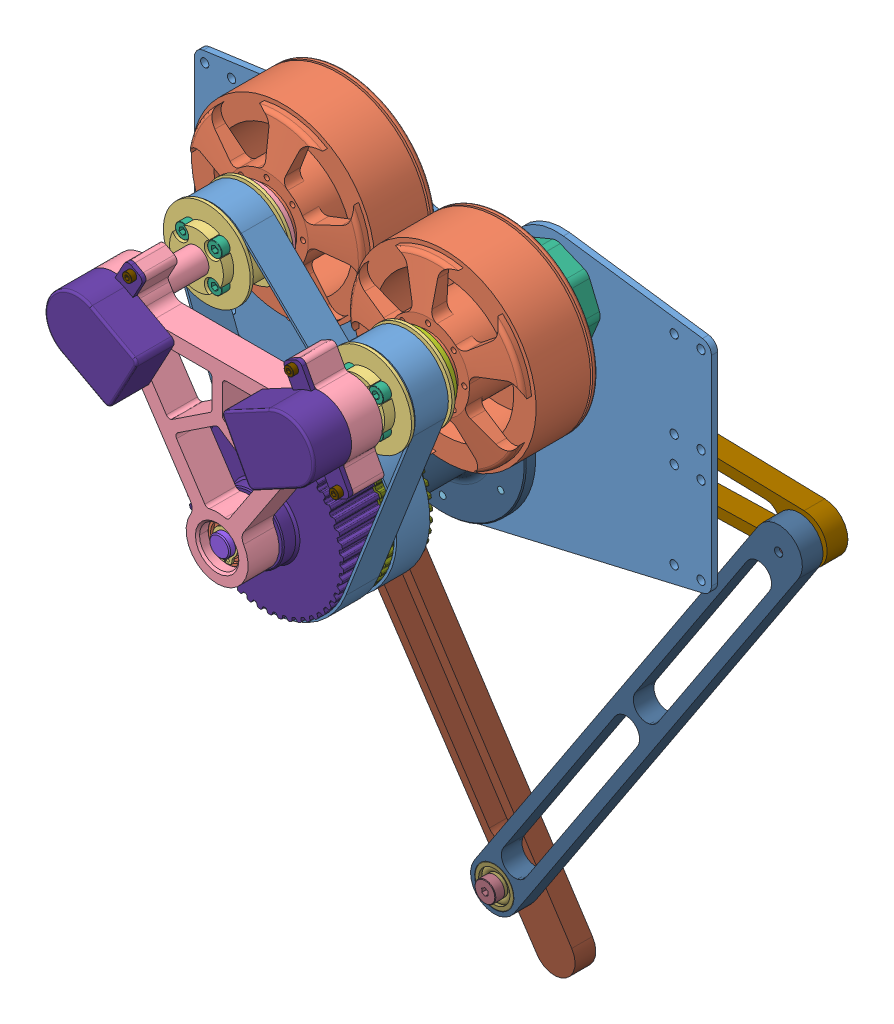
SolidWorks assembly Assembly, configuration Default. Lengths in mm.
Overall size (312.75 390.32 178.8).
163 component instances, 37 part files, 104 mates.
Components (placement in the parent):
- Mounting Plate-1: Mounting Plate [Default] at (803.8236 318.9692 0) size (250 143.05 3)
- Long Motor Assembly-1: Long Motor Assembly [Default] at (703.2032 181.8732 -91.3778) size (125.3 125.3 113)
  - T-Motor U10 KV80-1: T-Motor U10 KV80 [Default] at (50.6204 137.0959 94.3778) x (0.707107 -0.707107 0) z (0 0 1) size (88.6 88.6 43)
  - Timing Belt Pulley-1: Timing Belt Pulley [Default] at (50.6204 137.0959 142.3778) x (-0.707107 0.707107 0) z (0 0 -1) size (42 42 26)
  - Motor Shaft Long-1: Motor Shaft Long [Default] at (50.6204 137.0959 137.3778) x (0 -1 0) z (0 0 1) size (34 34 90)
  - ISO 10642 - M4 x 12 - 12C-9: ISO 10642 - M4 x 12 - 12C [ISO 10642 - M4 x 12 - 12C] at (50.6204 148.5959 142.3578) x (0 0 -1) z (0.997572 0.069644 0) size (12 7.53 7.53)
  - ISO 10642 - M4 x 12 - 12C-10: ISO 10642 - M4 x 12 - 12C [ISO 10642 - M4 x 12 - 12C] at (62.1204 137.0959 142.3578) x (0 0 -1) z (1 0 0) size (12 7.53 7.53)
  - ISO 10642 - M4 x 12 - 12C-11: ISO 10642 - M4 x 12 - 12C [ISO 10642 - M4 x 12 - 12C] at (39.1204 137.0959 142.3578) x (0 0 -1) z (1 0 0) size (12 7.53 7.53)
  - ISO 10642 - M4 x 12 - 12C-12: ISO 10642 - M4 x 12 - 12C [ISO 10642 - M4 x 12 - 12C] at (50.6204 125.5959 142.3578) x (0 0 -1) z (1 0 0) size (12 7.53 7.53)
  - ISO 4762 M4 x 25 - 25C-2: ISO 4762 M4 x 25 - 25C [PreviewCfg] at (58.3986 144.8741 167.3778) x (0 0 -1) z (1 0 0) size (29 7 7)
  - ISO 4762 M4 x 25 - 25C-4: ISO 4762 M4 x 25 - 25C [ISO 4762 M4 x 25 - 25C] at (42.8422 144.8741 167.3778) x (0 0 -1) z (0.999681 -0.025261 0) size (29 7 7)
  - ISO 4762 M4 x 25 - 25C-6: ISO 4762 M4 x 25 - 25C [ISO 4762 M4 x 25 - 25C] at (42.8422 129.3178 167.3778) x (0 0 -1) z (1 0 0) size (29 7 7)
  - ISO 4762 M4 x 25 - 25C-8: ISO 4762 M4 x 25 - 25C [ISO 4762 M4 x 25 - 25C] at (58.3986 129.3178 167.3778) x (0 0 -1) z (1 0 0) size (29 7 7)
- Short Motor Assembly-1: Short Motor Assembly [Default] at (703.2032 181.8732 -91.3778) size (125.3 125.3 91)
  - T-Motor U10 KV80-1: T-Motor U10 KV80 [Default] at (150.6204 137.0959 116.3778) x (0.707107 0.707107 0) z (0 0 1) size (88.6 88.6 43)
  - Timing Belt Pulley-1: Timing Belt Pulley [Default] at (150.6204 137.0959 164.3778) x (0.707107 0.707107 0) z (0 0 -1) size (42 42 26)
  - Motor Shaft Short-1: Motor Shaft Short [Default] at (150.6204 137.0959 159.3778) x (0 1 0) z (0 0 1) size (34 34 68)
  - ISO 10642 - M4 x 12 - 12C-9: ISO 10642 - M4 x 12 - 12C [ISO 10642 - M4 x 12 - 12C] at (139.1204 137.0959 164.3578) x (0 0 -1) z (1 -0.000264 0) size (12 7.53 7.53)
  - ISO 10642 - M4 x 12 - 12C-10: ISO 10642 - M4 x 12 - 12C [ISO 10642 - M4 x 12 - 12C] at (150.6204 148.5959 164.3578) x (0 0 -1) z (1 0 0) size (12 7.53 7.53)
  - ISO 10642 - M4 x 12 - 12C-11: ISO 10642 - M4 x 12 - 12C [ISO 10642 - M4 x 12 - 12C] at (162.1204 137.0959 164.3578) x (0 0 -1) z (1 0 0) size (12 7.53 7.53)
  - ISO 4762 M4 x 25 - 25C-2: ISO 4762 M4 x 25 - 25C [PreviewCfg] at (142.8422 144.8741 189.3778) x (0 0 -1) z (1 0 0) size (29 7 7)
  - ISO 4762 M4 x 25 - 25C-4: ISO 4762 M4 x 25 - 25C [ISO 4762 M4 x 25 - 25C] at (158.3986 129.3178 189.3778) x (0 0 -1) z (1 0 0) size (29 7 7)
  - ISO 4762 M4 x 25 - 25C-6: ISO 4762 M4 x 25 - 25C [ISO 4762 M4 x 25 - 25C] at (158.3986 144.8741 189.3778) x (0 0 -1) z (1 0 0) size (29 7 7)
  - ISO 10642 - M4 x 12 - 12C-12: ISO 10642 - M4 x 12 - 12C [ISO 10642 - M4 x 12 - 12C] at (150.6204 125.5959 164.3578) x (0 0 -1) z (1 0 0) size (12 7.53 7.53)
  - ISO 4762 M4 x 25 - 25C-8: ISO 4762 M4 x 25 - 25C [ISO 4762 M4 x 25 - 25C] at (142.8422 129.3178 189.3778) x (0 0 -1) z (1 0 0) size (29 7 7)
- Coaxial Shaft Assembly-1: Coaxial Shaft Assembly [Default] at (709.5255 181.8732 -91.3778) size (109.28 109.28 155)
  - Inner Shaft-1: Inner Shaft [Default] at (94.2981 61.5422 207.3778) x (0 0 -1) z (1 0 0) size (155 12 12)
  - Outer Shaft-1: Outer Shaft [Default] at (94.2981 61.5422 163.3778) x (0 0 -1) z (-1 0 0) size (100.5 20 20)
  - Flange-1: Flange [Default] at (94.2981 61.5422 94.3778) x (-0.866025 0.5 0) z (0 0 1) size (80 80 40)
  - SKF - 61804 - 18,SI,NC,18_68-5: SKF - 61804 - 18,SI,NC,18_68 [SKF - 61804 - 18,SI,NC,18_68] at (94.2981 61.5422 97.8778) x (0 0 1) z (-0.071685 -0.997427 0) size (7 32 32)
  - SKF - 61804 - 18,SI,NC,18_68-6: SKF - 61804 - 18,SI,NC,18_68 [SKF - 61804 - 18,SI,NC,18_68] at (94.2981 61.5422 130.8778) x (0 0 1) z (-1 0 0) size (7 32 32)
  - Circlip DIN 471 - 20 x 1.2-3: Circlip DIN 471 - 20 x 1.2 [Circlip DIN 471 - 20 x 1.2] at (94.2981 61.5422 93.0778) x (-1 0 0) z (0 0 -1) size (22.81 25.6 1.2)
  - HK_1210-1: HK_1210 [Default] at (94.2981 61.5422 163.3778) x (0 0 -1) z (1 0 0) size (10 16 16)
    - _HK_1210_PART1_2-1: _HK_1210_PART1_2 [Default] at origin size (10 16 16)
    - _HK_1210_PART2_4-1: _HK_1210_PART2_4 [Default] at origin size (6.3 1.5 1.5)
    - _HK_1210_PART2_4-2: _HK_1210_PART2_4 [Default] x (1 0 0) z (0 0.34202 0.939693) size (6.3 1.5 1.5)
    - _HK_1210_PART2_4-3: _HK_1210_PART2_4 [Default] x (1 0 0) z (0 0.642788 0.766044) size (6.3 1.5 1.5)
    - _HK_1210_PART2_4-4: _HK_1210_PART2_4 [Default] x (1 0 0) z (0 0.866025 0.5) size (6.3 1.5 1.5)
    - _HK_1210_PART2_4-5: _HK_1210_PART2_4 [Default] x (1 0 0) z (0 0.984808 0.173648) size (6.3 1.5 1.5)
    - _HK_1210_PART2_4-6: _HK_1210_PART2_4 [Default] x (1 0 0) z (0 0.984808 -0.173648) size (6.3 1.5 1.5)
    - _HK_1210_PART2_4-7: _HK_1210_PART2_4 [Default] x (1 0 0) z (0 0.866025 -0.5) size (6.3 1.5 1.5)
    - _HK_1210_PART2_4-8: _HK_1210_PART2_4 [Default] x (1 0 0) z (0 0.642788 -0.766044) size (6.3 1.5 1.5)
    - _HK_1210_PART2_4-9: _HK_1210_PART2_4 [Default] x (1 0 0) z (0 0.34202 -0.939693) size (6.3 1.5 1.5)
    - _HK_1210_PART2_4-10: _HK_1210_PART2_4 [Default] x (1 0 0) z (0 0 -1) size (6.3 1.5 1.5)
    - _HK_1210_PART2_4-11: _HK_1210_PART2_4 [Default] x (1 0 0) z (0 -0.34202 -0.939693) size (6.3 1.5 1.5)
    - _HK_1210_PART2_4-12: _HK_1210_PART2_4 [Default] x (1 0 0) z (0 -0.642788 -0.766044) size (6.3 1.5 1.5)
    - _HK_1210_PART2_4-13: _HK_1210_PART2_4 [Default] x (1 0 0) z (0 -0.866025 -0.5) size (6.3 1.5 1.5)
    - _HK_1210_PART2_4-14: _HK_1210_PART2_4 [Default] x (1 0 0) z (0 -0.984808 -0.173648) size (6.3 1.5 1.5)
    - _HK_1210_PART2_4-15: _HK_1210_PART2_4 [Default] x (1 0 0) z (0 -0.984808 0.173648) size (6.3 1.5 1.5)
    - _HK_1210_PART2_4-16: _HK_1210_PART2_4 [Default] x (1 0 0) z (0 -0.866025 0.5) size (6.3 1.5 1.5)
    - _HK_1210_PART2_4-17: _HK_1210_PART2_4 [Default] x (1 0 0) z (0 -0.642788 0.766044) size (6.3 1.5 1.5)
    - _HK_1210_PART2_4-18: _HK_1210_PART2_4 [Default] x (1 0 0) z (0 -0.34202 0.939693) size (6.3 1.5 1.5)
    - _HK_1210_PART3_23-1: _HK_1210_PART3_23 [Default] at origin size (6.3 1.5 1.5)
    - _HK_1210_PART3_23-2: _HK_1210_PART3_23 [Default] x (1 0 0) z (0 0.34202 0.939693) size (6.3 1.5 1.5)
    - _HK_1210_PART3_23-3: _HK_1210_PART3_23 [Default] x (1 0 0) z (0 0.642788 0.766044) size (6.3 1.5 1.5)
    - _HK_1210_PART3_23-4: _HK_1210_PART3_23 [Default] x (1 0 0) z (0 0.866025 0.5) size (6.3 1.5 1.5)
    - _HK_1210_PART3_23-5: _HK_1210_PART3_23 [Default] x (1 0 0) z (0 0.984808 0.173648) size (6.3 1.5 1.5)
    - _HK_1210_PART3_23-6: _HK_1210_PART3_23 [Default] x (1 0 0) z (0 0.984808 -0.173648) size (6.3 1.5 1.5)
    - _HK_1210_PART3_23-7: _HK_1210_PART3_23 [Default] x (1 0 0) z (0 0.866025 -0.5) size (6.3 1.5 1.5)
    - _HK_1210_PART3_23-8: _HK_1210_PART3_23 [Default] x (1 0 0) z (0 0.642788 -0.766044) size (6.3 1.5 1.5)
    - _HK_1210_PART3_23-9: _HK_1210_PART3_23 [Default] x (1 0 0) z (0 0.34202 -0.939693) size (6.3 1.5 1.5)
    - _HK_1210_PART3_23-10: _HK_1210_PART3_23 [Default] x (1 0 0) z (0 0 -1) size (6.3 1.5 1.5)
    - _HK_1210_PART3_23-11: _HK_1210_PART3_23 [Default] x (1 0 0) z (0 -0.34202 -0.939693) size (6.3 1.5 1.5)
    - _HK_1210_PART3_23-12: _HK_1210_PART3_23 [Default] x (1 0 0) z (0 -0.642788 -0.766044) size (6.3 1.5 1.5)
    - _HK_1210_PART3_23-13: _HK_1210_PART3_23 [Default] x (1 0 0) z (0 -0.866025 -0.5) size (6.3 1.5 1.5)
    - _HK_1210_PART3_23-14: _HK_1210_PART3_23 [Default] x (1 0 0) z (0 -0.984808 -0.173648) size (6.3 1.5 1.5)
    - _HK_1210_PART3_23-15: _HK_1210_PART3_23 [Default] x (1 0 0) z (0 -0.984808 0.173648) size (6.3 1.5 1.5)
    - _HK_1210_PART3_23-16: _HK_1210_PART3_23 [Default] x (1 0 0) z (0 -0.866025 0.5) size (6.3 1.5 1.5)
    - _HK_1210_PART3_23-17: _HK_1210_PART3_23 [Default] x (1 0 0) z (0 -0.642788 0.766044) size (6.3 1.5 1.5)
    - _HK_1210_PART3_23-18: _HK_1210_PART3_23 [Default] x (1 0 0) z (0 -0.34202 0.939693) size (6.3 1.5 1.5)
  - HK_1210-2: HK_1210 [Default] at (94.2981 61.5422 72.8778) x (0 0 -1) z (1 0 0) size (10 16 16)
    - _HK_1210_PART1_2-1: _HK_1210_PART1_2 [Default] at origin size (10 16 16)
    - _HK_1210_PART2_4-1: _HK_1210_PART2_4 [Default] at origin size (6.3 1.5 1.5)
    - _HK_1210_PART2_4-2: _HK_1210_PART2_4 [Default] x (1 0 0) z (0 0.34202 0.939693) size (6.3 1.5 1.5)
    - _HK_1210_PART2_4-3: _HK_1210_PART2_4 [Default] x (1 0 0) z (0 0.642788 0.766044) size (6.3 1.5 1.5)
    - _HK_1210_PART2_4-4: _HK_1210_PART2_4 [Default] x (1 0 0) z (0 0.866025 0.5) size (6.3 1.5 1.5)
    - _HK_1210_PART2_4-5: _HK_1210_PART2_4 [Default] x (1 0 0) z (0 0.984808 0.173648) size (6.3 1.5 1.5)
    - _HK_1210_PART2_4-6: _HK_1210_PART2_4 [Default] x (1 0 0) z (0 0.984808 -0.173648) size (6.3 1.5 1.5)
    - _HK_1210_PART2_4-7: _HK_1210_PART2_4 [Default] x (1 0 0) z (0 0.866025 -0.5) size (6.3 1.5 1.5)
    - _HK_1210_PART2_4-8: _HK_1210_PART2_4 [Default] x (1 0 0) z (0 0.642788 -0.766044) size (6.3 1.5 1.5)
    - _HK_1210_PART2_4-9: _HK_1210_PART2_4 [Default] x (1 0 0) z (0 0.34202 -0.939693) size (6.3 1.5 1.5)
    - _HK_1210_PART2_4-10: _HK_1210_PART2_4 [Default] x (1 0 0) z (0 0 -1) size (6.3 1.5 1.5)
    - _HK_1210_PART2_4-11: _HK_1210_PART2_4 [Default] x (1 0 0) z (0 -0.34202 -0.939693) size (6.3 1.5 1.5)
    - _HK_1210_PART2_4-12: _HK_1210_PART2_4 [Default] x (1 0 0) z (0 -0.642788 -0.766044) size (6.3 1.5 1.5)
    - _HK_1210_PART2_4-13: _HK_1210_PART2_4 [Default] x (1 0 0) z (0 -0.866025 -0.5) size (6.3 1.5 1.5)
    - _HK_1210_PART2_4-14: _HK_1210_PART2_4 [Default] x (1 0 0) z (0 -0.984808 -0.173648) size (6.3 1.5 1.5)
    - _HK_1210_PART2_4-15: _HK_1210_PART2_4 [Default] x (1 0 0) z (0 -0.984808 0.173648) size (6.3 1.5 1.5)
    - _HK_1210_PART2_4-16: _HK_1210_PART2_4 [Default] x (1 0 0) z (0 -0.866025 0.5) size (6.3 1.5 1.5)
    - _HK_1210_PART2_4-17: _HK_1210_PART2_4 [Default] x (1 0 0) z (0 -0.642788 0.766044) size (6.3 1.5 1.5)
    - _HK_1210_PART2_4-18: _HK_1210_PART2_4 [Default] x (1 0 0) z (0 -0.34202 0.939693) size (6.3 1.5 1.5)
    - _HK_1210_PART3_23-1: _HK_1210_PART3_23 [Default] at origin size (6.3 1.5 1.5)
    - _HK_1210_PART3_23-2: _HK_1210_PART3_23 [Default] x (1 0 0) z (0 0.34202 0.939693) size (6.3 1.5 1.5)
    - _HK_1210_PART3_23-3: _HK_1210_PART3_23 [Default] x (1 0 0) z (0 0.642788 0.766044) size (6.3 1.5 1.5)
    - _HK_1210_PART3_23-4: _HK_1210_PART3_23 [Default] x (1 0 0) z (0 0.866025 0.5) size (6.3 1.5 1.5)
    - _HK_1210_PART3_23-5: _HK_1210_PART3_23 [Default] x (1 0 0) z (0 0.984808 0.173648) size (6.3 1.5 1.5)
    - _HK_1210_PART3_23-6: _HK_1210_PART3_23 [Default] x (1 0 0) z (0 0.984808 -0.173648) size (6.3 1.5 1.5)
    - _HK_1210_PART3_23-7: _HK_1210_PART3_23 [Default] x (1 0 0) z (0 0.866025 -0.5) size (6.3 1.5 1.5)
    - _HK_1210_PART3_23-8: _HK_1210_PART3_23 [Default] x (1 0 0) z (0 0.642788 -0.766044) size (6.3 1.5 1.5)
    - _HK_1210_PART3_23-9: _HK_1210_PART3_23 [Default] x (1 0 0) z (0 0.34202 -0.939693) size (6.3 1.5 1.5)
    - _HK_1210_PART3_23-10: _HK_1210_PART3_23 [Default] x (1 0 0) z (0 0 -1) size (6.3 1.5 1.5)
    - _HK_1210_PART3_23-11: _HK_1210_PART3_23 [Default] x (1 0 0) z (0 -0.34202 -0.939693) size (6.3 1.5 1.5)
    - _HK_1210_PART3_23-12: _HK_1210_PART3_23 [Default] x (1 0 0) z (0 -0.642788 -0.766044) size (6.3 1.5 1.5)
    - _HK_1210_PART3_23-13: _HK_1210_PART3_23 [Default] x (1 0 0) z (0 -0.866025 -0.5) size (6.3 1.5 1.5)
    - _HK_1210_PART3_23-14: _HK_1210_PART3_23 [Default] x (1 0 0) z (0 -0.984808 -0.173648) size (6.3 1.5 1.5)
    - _HK_1210_PART3_23-15: _HK_1210_PART3_23 [Default] x (1 0 0) z (0 -0.984808 0.173648) size (6.3 1.5 1.5)
    - _HK_1210_PART3_23-16: _HK_1210_PART3_23 [Default] x (1 0 0) z (0 -0.866025 0.5) size (6.3 1.5 1.5)
    - _HK_1210_PART3_23-17: _HK_1210_PART3_23 [Default] x (1 0 0) z (0 -0.642788 0.766044) size (6.3 1.5 1.5)
    - _HK_1210_PART3_23-18: _HK_1210_PART3_23 [Default] x (1 0 0) z (0 -0.34202 0.939693) size (6.3 1.5 1.5)
  - Outer Timing Belt Gear-1: Outer Timing Belt Gear [Default] at (94.2981 61.5422 163.3778) x (1 0 0) z (0 0 -1) size (76.29 76.29 29)
  - Inner Timing Belt Gear-1: Inner Timing Belt Gear [Default] at (94.2981 61.5422 164.3778) size (76.29 76.29 28)
  - ISO 8734 - 4 x 32 - A - St-3: ISO 8734 - 4 x 32 - A - St [ISO 8734 - 4 x 32 - A - St] at (94.2981 45.5422 188.8778) x (0 1 0) z (0.480016 0 0.87726) size (32 4 4)
  - ISO 4762 M3 x 12 - 12C-3: ISO 4762 M3 x 12 - 12C [ISO 4762 M3 x 12 - 12C] at (94.2981 39.5422 138.8778) x (0 1 0) z (0.922632 0 -0.385681) size (15 5.5 5.5)
  - ISO 4762 M3 x 12 - 12C-4: ISO 4762 M3 x 12 - 12C [ISO 4762 M3 x 12 - 12C] at (94.2981 83.5422 138.8778) x (0 -1 0) z (0.974179 0 0.225776) size (15 5.5 5.5)
- SKF - 61800 - 14,SI,NC,14_68-5: SKF - 61800 - 14,SI,NC,14_68 [SKF - 61800 - 14,SI,NC,14_68] at (803.8236 243.4155 109.5) x (0 0 1) z (-0.331189 0.943564 0) size (5 19 19)
- Circlip DIN 471 - 10 x 1-8: Circlip DIN 471 - 10 x 1 [Circlip DIN 471 - 10 x 1] at (803.8236 243.4155 113.1) size (12.16 14.7 1)
- Support Brace-1: Support Brace [Default] at (803.8236 318.9692 109.5) x (-1 0 0) z (0 0 -1) size (131.26 114.86 15)
- SKF - 61800 - 14,SI,NC,14_68-6: SKF - 61800 - 14,SI,NC,14_68 [SKF - 61800 - 14,SI,NC,14_68] at (753.8236 318.9692 109.5) x (0 0 -1) z (-0.924864 0.380297 0) size (5 19 19)
- SKF - 61800 - 14,SI,NC,14_68-7: SKF - 61800 - 14,SI,NC,14_68 [SKF - 61800 - 14,SI,NC,14_68] at (853.8236 318.9692 109.5) x (0 0 -1) z (-0.072342 0.99738 0) size (5 19 19)
- Circlip DIN 471 - 10 x 1-9: Circlip DIN 471 - 10 x 1 [Circlip DIN 471 - 10 x 1] at (753.8236 318.9692 113.1) x (0.999962 0.008683 0) z (0 0 1) size (12.16 14.7 1)
- Circlip DIN 471 - 10 x 1-10: Circlip DIN 471 - 10 x 1 [Circlip DIN 471 - 10 x 1] at (853.8236 318.9692 113.1) x (0.996379 0.085026 0) z (0 0 1) size (12.16 14.7 1)
- ISO 4762 M4 x 8 - 8C-38: ISO 4762 M4 x 8 - 8C [ISO 4762 M4 x 8 - 8C] at (753.8236 334.9692 -4) x (0 0 1) z (-1 0 0) size (12 7 7)
- ISO 4762 M4 x 8 - 8C-39: ISO 4762 M4 x 8 - 8C [ISO 4762 M4 x 8 - 8C] at (769.8236 318.9692 -4) x (0 0 1) z (-1 0 0) size (12 7 7)
- ISO 4762 M4 x 8 - 8C-40: ISO 4762 M4 x 8 - 8C [ISO 4762 M4 x 8 - 8C] at (753.8236 302.9692 -4) x (0 0 1) z (-1 0 0) size (12 7 7)
- ISO 4762 M4 x 8 - 8C-41: ISO 4762 M4 x 8 - 8C [ISO 4762 M4 x 8 - 8C] at (737.8236 318.9692 -4) x (0 0 1) z (-1 0 0) size (12 7 7)
- Motor Mounting-1: Motor Mounting [Default] at (853.8236 318.9692 3) size (42.47 42.47 22)
- ISO 4762 M4 x 30 - 20C-40: ISO 4762 M4 x 30 - 20C [ISO 4762 M4 x 30 - 20C] at (853.8236 334.9692 -4) x (0 0 1) z (-1 0 0) size (34 7 7)
- ISO 4762 M4 x 30 - 20C-41: ISO 4762 M4 x 30 - 20C [ISO 4762 M4 x 30 - 20C] at (869.8236 318.9692 -4) x (0 0 1) z (-1 0 0) size (34 7 7)
- ISO 4762 M4 x 30 - 20C-42: ISO 4762 M4 x 30 - 20C [ISO 4762 M4 x 30 - 20C] at (853.8236 302.9692 -4) x (0 0 1) z (-1 0 0) size (34 7 7)
- ISO 4762 M4 x 30 - 20C-43: ISO 4762 M4 x 30 - 20C [ISO 4762 M4 x 30 - 20C] at (837.8236 318.9692 -4) x (0 0 1) z (-1 0 0) size (34 7 7)
- ISO 4762 M4 x 8 - 8C-42: ISO 4762 M4 x 8 - 8C [ISO 4762 M4 x 8 - 8C] at (803.8236 275.9155 -4) x (0 0 1) z (-1 0 0) size (12 7 7)
- ISO 4762 M4 x 8 - 8C-43: ISO 4762 M4 x 8 - 8C [ISO 4762 M4 x 8 - 8C] at (775.6778 259.6655 -4) x (0 0 1) z (-1 0 0) size (12 7 7)
- ISO 4762 M4 x 8 - 8C-44: ISO 4762 M4 x 8 - 8C [ISO 4762 M4 x 8 - 8C] at (775.6778 227.1655 -4) x (0 0 1) z (-1 0 0) size (12 7 7)
- ISO 4762 M4 x 8 - 8C-45: ISO 4762 M4 x 8 - 8C [ISO 4762 M4 x 8 - 8C] at (831.9694 259.6655 -4) x (0 0 1) z (-1 0 0) size (12 7 7)
- ISO 4762 M4 x 8 - 8C-46: ISO 4762 M4 x 8 - 8C [ISO 4762 M4 x 8 - 8C] at (831.9694 227.1655 -4) x (0 0 1) z (-1 0 0) size (12 7 7)
- ISO 4762 M4 x 8 - 8C-47: ISO 4762 M4 x 8 - 8C [ISO 4762 M4 x 8 - 8C] at (803.8236 210.9155 -4) x (0 0 1) z (-1 0 0) size (12 7 7)
- Leg Assembly-2: Leg Assembly [Default] at (881.8415 93.4592 582.2565) x (-0.999747 -0.022471 0) z (0 0 -1) size (306.78 269.08 31)
  - Outer Short Link-1: Outer Short Link [Default] at (74.6286 151.6715 599.2565) x (-0.022471 0.999747 0) z (0.999747 0.022471 0) size (34 10 164)
  - Inner Short Link-1: Inner Short Link [Default] at (74.6286 151.6715 611.2565) x (0.022471 -0.999747 0) z (-0.999747 -0.022471 0) size (33.99 10 164)
  - Long Link-1: Long Link [Default] at (-62.8367 148.5818 609.2565) x (0.568628 -0.822595 0) z (0.822595 0.568628 0) size (273 10 23)
  - Extra Long Link-1: Extra Long Link [Default] at (212.0939 154.7613 621.2565) x (-0.531094 -0.847313 0) z (0.847313 -0.531094 0) size (301.49 10 23)
  - SKF - 626 - 8,SI,NC,8_68-8: SKF - 626 - 8,SI,NC,8_68 [SKF - 626 - 8,SI,NC,8_68] at (212.0939 154.7613 602.2565) x (0 0 -1) z (0.999791 0.020442 0) size (6 19 19)
  - ISO 7379 - 6 x 10 --- C-7: ISO 7379 - 6 x 10 --- C [ISO 7379 - 6 x 10 --- C] at (212.0939 154.7613 594.7565) x (0 0 1) z (0.999947 -0.010306 0) size (24.25 10 10)
  - Leg Spacer-1: Leg Spacer [Default] at (212.0939 154.7613 611.2565) x (-0.080045 0.996791 0) z (-0.996791 -0.080045 0) size (8.2 6 8.2)
  - SKF - 626 - 8,SI,NC,8_68-9: SKF - 626 - 8,SI,NC,8_68 [SKF - 626 - 8,SI,NC,8_68] at (-62.8367 148.5818 618.2565) x (0 0 1) z (-1 0 0) size (6 19 19)
  - SKF - 626 - 8,SI,NC,8_68-10: SKF - 626 - 8,SI,NC,8_68 [SKF - 626 - 8,SI,NC,8_68] at (79.3203 -57.0669 602.2565) x (0 0 -1) z (1 0 0) size (6 19 19)
  - ISO 7379 - 6 x 10 --- C-8: ISO 7379 - 6 x 10 --- C [ISO 7379 - 6 x 10 --- C] at (79.3203 -57.0669 594.7565) x (0 0 1) z (-1 0 0) size (24.25 10 10)
  - Leg Spacer-2: Leg Spacer [Default] at (79.3203 -57.0669 605.2565) x (0.117154 0.993114 0) z (0.993114 -0.117154 0) size (8.2 6 8.2)
  - ISO 7379 - 6 x 10 --- C-9: ISO 7379 - 6 x 10 --- C [ISO 7379 - 6 x 10 --- C] at (-62.8367 148.5818 625.7565) x (0 0 -1) z (1 0 0) size (24.25 10 10)
  - Leg Spacer-3: Leg Spacer [Default] at (-62.8367 148.5818 609.2565) x (0.995138 0.09849 0) z (0.09849 -0.995138 0) size (8.2 6 8.2)
- ISO 4029 - M4 x 8-C-9: ISO 4029 - M4 x 8-C [ISO 4029 - M4 x 8-C] at (803.8236 229.4994 -34) x (0 1 0) z (-0.347527 0 -0.93767) size (8 4 4)
- ISO 4029 - M4 x 8-C-10: ISO 4029 - M4 x 8-C [ISO 4029 - M4 x 8-C] at (803.8236 225.4656 -22) x (0 1 0) z (-0.06505 0 -0.997882) size (8 4 4)
- ISO 4029 - M4 x 8-C-11: ISO 4029 - M4 x 8-C [ISO 4029 - M4 x 8-C] at (803.8236 257.3315 -34) x (0 -1 0) z (0.502893 0 -0.864349) size (8 4 4)
- ISO 4029 - M4 x 8-C-12: ISO 4029 - M4 x 8-C [ISO 4029 - M4 x 8-C] at (803.8236 261.3653 -22) x (0 -1 0) z (-0.029243 0 -0.999572) size (8 4 4)
- Encoder Shaft-1: Encoder Shaft [Default] at (853.8236 318.9692 113) x (-0.51827 -0.855217 0) z (-0.855217 0.51827 0) size (12.1 18 12.1)
- Encoder Shaft-2: Encoder Shaft [Default] at (753.8236 318.9692 113) x (0.667835 -0.744309 0) z (-0.744309 -0.667835 0) size (12.1 18 12.1)
- HEDL-5640-A13 Encoder-1: HEDL-5640-A13 Encoder [Default] at (753.8236 318.9692 117) x (0.473352 0.880874 0) z (0.880874 -0.473352 0) size (52.1 18.3 41.1)
- HEDL-5640-A13 Encoder-2: HEDL-5640-A13 Encoder [Default] at (853.8236 318.9692 117) x (0.473352 -0.880874 0) z (-0.880874 -0.473352 0) size (52.1 18.3 41.1)
- ISO 4762 M2.5 x 12 - 12C-6: ISO 4762 M2.5 x 12 - 12C [ISO 4762 M2.5 x 12 - 12C] at (764.7107 339.2292 121.5) x (0 0 -1) z (1 0 0) size (14.5 4.5 4.5)
- ISO 4762 M2.5 x 12 - 12C-7: ISO 4762 M2.5 x 12 - 12C [ISO 4762 M2.5 x 12 - 12C] at (742.9365 298.7091 121.5) x (0 0 -1) z (1 0 0) size (14.5 4.5 4.5)
- ISO 4762 M2.5 x 12 - 12C-8: ISO 4762 M2.5 x 12 - 12C [ISO 4762 M2.5 x 12 - 12C] at (842.9365 339.2292 121.5) x (0 0 -1) z (1 0 0) size (14.5 4.5 4.5)
- ISO 4762 M2.5 x 12 - 12C-9: ISO 4762 M2.5 x 12 - 12C [ISO 4762 M2.5 x 12 - 12C] at (864.7107 298.7091 121.5) x (0 0 -1) z (1 0 0) size (14.5 4.5 4.5)
- Contitech T5 365mm Timing Belt-1: Contitech T5 365mm Timing Belt [Default] at (803.8236 243.4155 69.5) x (0 0 -1) z (0.833926 0.551876 0) size (16 150.29 78.79)
- Contitech T5 365mm Timing Belt-2: Contitech T5 365mm Timing Belt [Default] at (803.8236 243.4155 91.5) x (0 0 -1) z (0.833926 -0.551876 0) size (16 150.29 78.79)
Mates (geometry in assembly coordinates):
- Concentric459: concentric: cylinder of Support Brace-1 through (50.6204 137.0959 233.0282) axis (0 0 -1) radius 10; cylinder of ? through (50.6204 137.0959 226.5991) axis (0 0 -1) radius 10
- Concentric4601: concentric: cylinder of Support Brace-1 through (50.6204 137.0959 203.2778) axis (0 0 -1) radius 10; cylinder of ? through (50.6204 137.0959 205.3778) axis (0 0 1) radius 10
- Coincident3141: coincident: plane of Support Brace-1 through (50.6204 147.0959 206.3778) normal (0 0 -1); plane of ? through (50.6204 137.0959 206.3778) normal (0 0 1)
- Concentric465: concentric: cylinder of Support Brace-1 through (150.6204 137.0959 203.2778) axis (0 0 -1) radius 9.5; cylinder of ? through (150.6204 137.0959 205.3778) axis (0 0 1) radius 10
- Coincident319: coincident: plane of Support Brace-1 through (150.6204 147.0959 206.3778) normal (0 0 -1); plane of ? through (150.6204 137.0959 206.3778) normal (0 0 1)
- Concentric470: concentric: cylinder of Support Brace-1 through (100.6204 57.0959 203.2778) axis (0 0 -1) radius 10; cylinder of ? through (100.6204 57.0959 205.3778) axis (0 0 1) radius 10
- Coincident324: coincident: plane of Support Brace-1 through (100.6204 47.0959 206.3778) normal (0 0 -1); plane of ? through (100.6204 57.0959 206.3778) normal (0 0 1)
- Concentric4602: concentric: cylinder of Support Brace-1 through (50.6204 137.0959 193.3778) axis (0 0 -1) radius 9.5; cylinder of SKF - 61800 - 14,SI,NC,14_68-6 through (50.6204 137.0959 221.5153) axis (0 0 -1) radius 9.5
- Coincident3142: coincident: plane of Support Brace-1 through (50.6204 144.5959 198.3778) normal (0 0 1); plane of SKF - 61800 - 14,SI,NC,14_68-6 through (47.1217 128.5872 198.3778) normal (0 0 -1)
- Concentric4622: concentric: cylinder of Mounting Plate-1 through (50.6204 153.0959 94.3778) axis (0 0 1) radius 2; cylinder of ISO 4762 M4 x 8 - 8C-38 through (50.6204 153.0959 55.6278) axis (0 0 -1) radius 3.5
- Coincident3149: coincident: plane of Mounting Plate-1 through (150.6204 137.0959 91.3778) normal (0 0 -1); plane of ISO 4762 M4 x 8 - 8C-38 through (50.6204 156.5959 91.3778) normal (0 0 1)
- Concentric46231: concentric: cylinder of Mounting Plate-1 through (66.6204 137.0959 94.3778) axis (0 0 1) radius 2; cylinder of ISO 4762 M4 x 8 - 8C-39 through (66.6204 137.0959 55.6278) axis (0 0 -1) radius 3.5
- Coincident31501: coincident: plane of Mounting Plate-1 through (150.6204 137.0959 91.3778) normal (0 0 -1); plane of ISO 4762 M4 x 8 - 8C-39 through (66.6204 140.5959 91.3778) normal (0 0 1)
- Concentric46241: concentric: cylinder of Mounting Plate-1 through (50.6204 121.0959 94.3778) axis (0 0 1) radius 2; cylinder of ISO 4762 M4 x 8 - 8C-40 through (50.6204 121.0959 55.6278) axis (0 0 -1) radius 3.5
- Coincident31511: coincident: plane of Mounting Plate-1 through (150.6204 137.0959 91.3778) normal (0 0 -1); plane of ISO 4762 M4 x 8 - 8C-40 through (50.6204 124.5959 91.3778) normal (0 0 1)
- Concentric46251: concentric: cylinder of Mounting Plate-1 through (34.6204 137.0959 94.3778) axis (0 0 1) radius 2; cylinder of ISO 4762 M4 x 8 - 8C-41 through (34.6204 137.0959 55.6278) axis (0 0 -1) radius 3.5
- Coincident31521: coincident: plane of Mounting Plate-1 through (150.6204 137.0959 91.3778) normal (0 0 -1); plane of ISO 4762 M4 x 8 - 8C-41 through (34.6204 140.5959 91.3778) normal (0 0 1)
- Concentric46482: concentric: cylinder of Mounting Plate-1 through (166.6204 137.0959 94.3778) axis (0 0 1) radius 2; cylinder of Motor Mounting-1 through (166.6204 137.0959 116.3778) axis (0 0 1) radius 2.15
- Concentric46483: concentric: cylinder of Mounting Plate-1 through (150.6204 153.0959 94.3778) axis (0 0 1) radius 2; cylinder of Motor Mounting-1 through (150.6204 153.0959 116.3778) axis (0 0 1) radius 2.15
- Concentric46484: concentric: cylinder of Mounting Plate-1 through (150.6204 153.0959 94.3778) axis (0 0 1) radius 2; cylinder of ISO 4762 M4 x 30 - 20C-40 through (150.6204 153.0959 55.6278) axis (0 0 -1) radius 3.5
- Coincident31754: coincident: plane of Mounting Plate-1 through (150.6204 137.0959 91.3778) normal (0 0 -1); plane of ISO 4762 M4 x 30 - 20C-40 through (150.6204 156.5959 91.3778) normal (0 0 1)
- Concentric464851: concentric: cylinder of Mounting Plate-1 through (166.6204 137.0959 94.3778) axis (0 0 1) radius 2; cylinder of ISO 4762 M4 x 30 - 20C-41 through (166.6204 137.0959 55.6278) axis (0 0 -1) radius 3.5
- Coincident317551: coincident: plane of Mounting Plate-1 through (150.6204 137.0959 91.3778) normal (0 0 -1); plane of ISO 4762 M4 x 30 - 20C-41 through (166.6204 140.5959 91.3778) normal (0 0 1)
- Concentric464861: concentric: cylinder of Mounting Plate-1 through (150.6204 121.0959 94.3778) axis (0 0 1) radius 2; cylinder of ISO 4762 M4 x 30 - 20C-42 through (150.6204 121.0959 55.6278) axis (0 0 -1) radius 3.5
- Coincident317561: coincident: plane of Mounting Plate-1 through (150.6204 137.0959 91.3778) normal (0 0 -1); plane of ISO 4762 M4 x 30 - 20C-42 through (150.6204 124.5959 91.3778) normal (0 0 1)
- Concentric464871: concentric: cylinder of Mounting Plate-1 through (134.6204 137.0959 94.3778) axis (0 0 1) radius 2; cylinder of ISO 4762 M4 x 30 - 20C-43 through (134.6204 137.0959 55.6278) axis (0 0 -1) radius 3.5
- Coincident317571: coincident: plane of Mounting Plate-1 through (150.6204 137.0959 91.3778) normal (0 0 -1); plane of ISO 4762 M4 x 30 - 20C-43 through (134.6204 140.5959 91.3778) normal (0 0 1)
- Concentric464872: concentric: cylinder of Mounting Plate-1 through (100.6204 94.0422 94.3778) axis (0 0 1) radius 2; cylinder of ISO 4762 M4 x 8 - 8C-42 through (100.6204 94.0422 55.6278) axis (0 0 -1) radius 3.5
- Coincident317572: coincident: plane of Mounting Plate-1 through (150.6204 137.0959 91.3778) normal (0 0 -1); plane of ISO 4762 M4 x 8 - 8C-42 through (100.6204 97.5422 91.3778) normal (0 0 1)
- Concentric4648731: concentric: cylinder of Mounting Plate-1 through (72.4746 77.7922 94.3778) axis (0 0 1) radius 2; cylinder of ISO 4762 M4 x 8 - 8C-43 through (72.4746 77.7922 55.6278) axis (0 0 -1) radius 3.5
- Coincident3175731: coincident: plane of Mounting Plate-1 through (150.6204 137.0959 91.3778) normal (0 0 -1); plane of ISO 4762 M4 x 8 - 8C-43 through (72.4746 81.2922 91.3778) normal (0 0 1)
- Concentric4648741: concentric: cylinder of Mounting Plate-1 through (72.4746 45.2922 94.3778) axis (0 0 1) radius 2; cylinder of ISO 4762 M4 x 8 - 8C-44 through (72.4746 45.2922 55.6278) axis (0 0 -1) radius 3.5
- Coincident3175741: coincident: plane of Mounting Plate-1 through (150.6204 137.0959 91.3778) normal (0 0 -1); plane of ISO 4762 M4 x 8 - 8C-44 through (72.4746 48.7922 91.3778) normal (0 0 1)
- Concentric4648751: concentric: cylinder of Mounting Plate-1 through (128.7662 77.7922 94.3778) axis (0 0 1) radius 2; cylinder of ISO 4762 M4 x 8 - 8C-45 through (128.7662 77.7922 55.6278) axis (0 0 -1) radius 3.5
- Coincident3175751: coincident: plane of Mounting Plate-1 through (150.6204 137.0959 91.3778) normal (0 0 -1); plane of ISO 4762 M4 x 8 - 8C-45 through (128.7662 81.2922 91.3778) normal (0 0 1)
- Concentric4648761: concentric: cylinder of Mounting Plate-1 through (128.7662 45.2922 94.3778) axis (0 0 1) radius 2; cylinder of ISO 4762 M4 x 8 - 8C-46 through (128.7662 45.2922 55.6278) axis (0 0 -1) radius 3.5
- Coincident3175761: coincident: plane of Mounting Plate-1 through (150.6204 137.0959 91.3778) normal (0 0 -1); plane of ISO 4762 M4 x 8 - 8C-46 through (128.7662 48.7922 91.3778) normal (0 0 1)
- Concentric4648771: concentric: cylinder of Mounting Plate-1 through (100.6204 29.0422 94.3778) axis (0 0 1) radius 2; cylinder of ISO 4762 M4 x 8 - 8C-47 through (100.6204 29.0422 55.6278) axis (0 0 -1) radius 3.5
- Coincident3175771: coincident: plane of Mounting Plate-1 through (150.6204 137.0959 91.3778) normal (0 0 -1); plane of ISO 4762 M4 x 8 - 8C-47 through (100.6204 32.5422 91.3778) normal (0 0 1)
- Coincident3175773: coincident: plane of Mounting Plate-1 through (150.6204 137.0959 94.3778) normal (0 0 1); plane of Coaxial Shaft Assembly-1/Flange-1 through (100.6204 61.5422 94.3778) normal (0 0 -1)
- Concentric4648775: concentric: cylinder of Mounting Plate-1 through (100.6204 61.5422 94.3778) axis (0 0 -1) radius 14.5; cylinder of Coaxial Shaft Assembly-1/Flange-1 through (100.6204 61.5422 150.679) axis (0 0 1) radius 14.5
- Concentric4648776: concentric: cylinder of Mounting Plate-1 through (72.4746 77.7922 94.3778) axis (0 0 1) radius 2; cylinder of Coaxial Shaft Assembly-1/Flange-1 through (72.4746 77.7922 94.3778) axis (0 0 1) radius 1.5
- Coincident3175775: coincident: plane of Mounting Plate-1 through (150.6204 137.0959 94.3778) normal (0 0 1); plane of Coaxial Shaft Assembly-1/SKF - 61804 - 18,SI,NC,18_68-5 through (86.4569 62.5602 94.3778) normal (0 0 -1)
- Concentric469: concentric: cylinder of Coaxial Shaft Assembly-1/Inner Shaft-1 through (100.6204 61.5422 52.3778) axis (0 0 -1) radius 4.8; cylinder of Circlip DIN 471 - 10 x 1-8 through (100.6204 61.5422 203.4778) axis (0 0 1) radius 4.8
- Coincident323: coincident: plane of Coaxial Shaft Assembly-1/Inner Shaft-1 through (100.6204 66.3422 204.4778) normal (0 0 -1); plane of Circlip DIN 471 - 10 x 1-8 through (100.6204 61.5422 204.4778) normal (0 0 1)
- Parallel7: parallel: plane of Circlip DIN 471 - 10 x 1-8 through (100.6204 61.5422 204.4778) normal (1 0 0); plane of Coaxial Shaft Assembly-1 through (6.3223 0 0) normal (1 0 0)
- Concentric468: concentric: cylinder of Coaxial Shaft Assembly-1/Inner Shaft-1 through (100.6204 61.5422 52.3778) axis (0 0 -1) radius 5; cylinder of SKF - 61800 - 14,SI,NC,14_68-5 through (100.6204 61.5422 180.2403) axis (0 0 1) radius 5
- Coincident322: coincident: plane of Coaxial Shaft Assembly-1/Inner Shaft-1 through (100.6204 67.5422 198.3778) normal (0 0 1); plane of SKF - 61800 - 14,SI,NC,14_68-5 through (106.612 63.6453 198.3778) normal (0 0 -1)
- Coincident3175782: coincident: plane of Mounting Plate-1 through (150.6204 137.0959 94.3778) normal (0 0 1); plane of Long Motor Assembly-1/T-Motor U10 KV80-1 through (50.6204 137.0959 94.3778) normal (0 0 -1)
- Concentric4648790: concentric: cylinder of Long Motor Assembly-1/T-Motor U10 KV80-1 through (66.6204 137.0959 94.3778) axis (0 0 -1) radius 1.65; cylinder of Mounting Plate-1 through (66.6204 137.0959 94.3778) axis (0 0 1) radius 2
- Concentric4648791: concentric: cylinder of Mounting Plate-1 through (50.6204 153.0959 94.3778) axis (0 0 1) radius 2; cylinder of Long Motor Assembly-1/T-Motor U10 KV80-1 through (50.6204 153.0959 94.3778) axis (0 0 -1) radius 1.65
- Concentric4648792: concentric: cylinder of Long Motor Assembly-1/Motor Shaft Long-1 through (50.6204 137.0959 117.3778) axis (0 0 -1) radius 5; cylinder of SKF - 61800 - 14,SI,NC,14_68-6 through (50.6204 137.0959 221.5153) axis (0 0 -1) radius 5
- Coincident3175784: coincident: plane of Long Motor Assembly-1/Motor Shaft Long-1 through (56.6204 137.0959 198.3778) normal (0 0 1); plane of SKF - 61800 - 14,SI,NC,14_68-6 through (48.6048 132.1942 198.3778) normal (0 0 -1)
- Concentric4648793: concentric: cylinder of Long Motor Assembly-1/Motor Shaft Long-1 through (50.6204 137.0959 117.3778) axis (0 0 -1) radius 4.8; cylinder of Circlip DIN 471 - 10 x 1-9 through (50.6204 137.0959 203.4778) axis (0 0 1) radius 4.8
- Coincident3175785: coincident: plane of Long Motor Assembly-1/Motor Shaft Long-1 through (55.4204 137.0959 204.4778) normal (0 0 -1); plane of Circlip DIN 471 - 10 x 1-9 through (50.6204 137.0959 204.4778) normal (0 0 1)
- Concentric4648794: concentric: cylinder of Long Motor Assembly-1/Motor Shaft Long-1 through (50.6204 137.0959 117.3778) axis (0 0 -1) radius 5; cylinder of Encoder Shaft-2 through (50.6204 137.0959 160.8629) axis (0 0 -1) radius 5.05
- Concentric4648795: concentric: cylinder of Mounting Plate-1 through (150.6204 153.0959 94.3778) axis (0 0 1) radius 2; cylinder of ? through (150.6204 153.0959 116.3778) axis (0 0 -1) radius 1.65
- Concentric4648796: concentric: cylinder of Mounting Plate-1 through (134.6204 137.0959 94.3778) axis (0 0 1) radius 2; cylinder of ? through (134.6204 137.0959 116.3778) axis (0 0 -1) radius 1.65
- Coincident3175788: coincident: plane of ? through (150.6204 137.0959 116.3778) normal (0 0 -1); plane of Motor Mounting-1 through (150.6204 137.0959 116.3778) normal (0 0 1)
- Distance4: distance = 1 mm: plane of Short Motor Assembly-1/Timing Belt Pulley-1 through (868.6728 304.1199 73) normal (0 0 -1); plane of Long Motor Assembly-1/Timing Belt Pulley-1 through (763.016 328.1615 72) normal (0 0 1)
- Coincident3175790: coincident: plane of Short Motor Assembly-1/Motor Shaft Short-1 through (144.6204 137.0959 198.3778) normal (0 0 1); plane of SKF - 61800 - 14,SI,NC,14_68-7 through (145.3343 136.7125 198.3778) normal (0 0 -1)
- Concentric4648798: concentric: cylinder of Short Motor Assembly-1/Motor Shaft Short-1 through (150.6204 137.0959 139.3778) axis (0 0 -1) radius 4.8; cylinder of Circlip DIN 471 - 10 x 1-10 through (150.6204 137.0959 203.4778) axis (0 0 1) radius 4.8
- Coincident3175791: coincident: plane of Short Motor Assembly-1/Motor Shaft Short-1 through (145.8204 137.0959 204.4778) normal (0 0 -1); plane of Circlip DIN 471 - 10 x 1-10 through (150.6204 137.0959 204.4778) normal (0 0 1)
- Concentric4648799: concentric: cylinder of Short Motor Assembly-1/Motor Shaft Short-1 through (150.6204 137.0959 139.3778) axis (0 0 -1) radius 5; cylinder of Encoder Shaft-1 through (150.6204 137.0959 160.8629) axis (0 0 -1) radius 5.05
- Coincident3175794: coincident: plane of ? through (59.8128 146.2883 163.3778) normal (0 0 1); plane of Coaxial Shaft Assembly-1/Outer Timing Belt Gear-1 through (100.6204 61.5422 163.3778) normal (0 0 1)
- Concentric4648804: concentric: cylinder of Short Motor Assembly-1/Motor Shaft Short-1 through (150.6204 137.0959 139.3778) axis (0 0 -1) radius 5; cylinder of SKF - 61800 - 14,SI,NC,14_68-7 through (150.6204 137.0959 221.5153) axis (0 0 -1) radius 5
- Tangent2: tangent: cylinder of Leg Assembly-2/Outer Short Link-1 through (100.6204 61.5422 64.3778) axis (0 0 1) radius 10; circle of ISO 4029 - M4 x 8-C-10
- Coincident3175795: coincident: plane of Support Brace-1 through (100.6204 61.5422 208.3778) normal (0 0 1); plane of HEDL-5640-A13 Encoder-1 through (50.6204 137.0959 208.3778) normal (0 0 -1)
- Concentric4648805: concentric: cylinder of Support Brace-1 through (39.7333 116.8358 208.3778) axis (0 0 1) radius 1.2; cylinder of HEDL-5640-A13 Encoder-1 through (39.7333 116.8358 210.3778) axis (0 0 -1) radius 1.25
- Concentric4648806: concentric: cylinder of Support Brace-1 through (61.5075 157.356 208.3778) axis (0 0 1) radius 1.2; cylinder of HEDL-5640-A13 Encoder-1 through (61.5075 157.356 210.3778) axis (0 0 -1) radius 1.25
- Coincident3175796: coincident: plane of Support Brace-1 through (100.6204 61.5422 208.3778) normal (0 0 1); plane of HEDL-5640-A13 Encoder-2 through (150.6204 137.0959 208.3778) normal (0 0 -1)
- Concentric4648807: concentric: cylinder of Support Brace-1 through (139.7333 157.356 208.3778) axis (0 0 1) radius 1.2; cylinder of HEDL-5640-A13 Encoder-2 through (139.7333 157.356 210.3778) axis (0 0 -1) radius 1.25
- Concentric4648808: concentric: cylinder of Support Brace-1 through (161.5075 116.8358 208.3778) axis (0 0 1) radius 1.2; cylinder of HEDL-5640-A13 Encoder-2 through (161.5075 116.8358 210.3778) axis (0 0 -1) radius 1.25
- Concentric4648810: concentric: cylinder of HEDL-5640-A13 Encoder-1 through (61.5075 157.356 210.3778) axis (0 0 -1) radius 1.25; cylinder of ISO 4762 M2.5 x 12 - 12C-6 through (61.5075 157.356 244.6278) axis (0 0 1) radius 2.25
- Coincident3175798: coincident: plane of HEDL-5640-A13 Encoder-1 through (59.7859 158.9056 210.3778) normal (0 0 1); plane of ISO 4762 M2.5 x 12 - 12C-6 through (61.5075 159.606 210.3778) normal (0 0 -1)
- Concentric46488111: concentric: cylinder of HEDL-5640-A13 Encoder-1 through (39.7333 116.8358 210.3778) axis (0 0 -1) radius 1.25; cylinder of ISO 4762 M2.5 x 12 - 12C-7 through (39.7333 116.8358 244.6278) axis (0 0 1) radius 2.25
- Coincident31757991: coincident: plane of HEDL-5640-A13 Encoder-1 through (59.7859 158.9056 210.3778) normal (0 0 1); plane of ISO 4762 M2.5 x 12 - 12C-7 through (39.7333 119.0858 210.3778) normal (0 0 -1)
- Concentric46488121: concentric: cylinder of HEDL-5640-A13 Encoder-2 through (139.7333 157.356 210.3778) axis (0 0 -1) radius 1.25; cylinder of ISO 4762 M2.5 x 12 - 12C-8 through (139.7333 157.356 244.6278) axis (0 0 1) radius 2.25
- Coincident31758001: coincident: plane of HEDL-5640-A13 Encoder-2 through (163.7498 117.4164 210.3778) normal (0 0 1); plane of ISO 4762 M2.5 x 12 - 12C-8 through (139.7333 159.606 210.3778) normal (0 0 -1)
- Concentric46488131: concentric: cylinder of HEDL-5640-A13 Encoder-2 through (161.5075 116.8358 210.3778) axis (0 0 -1) radius 1.25; cylinder of ISO 4762 M2.5 x 12 - 12C-9 through (161.5075 116.8358 244.6278) axis (0 0 1) radius 2.25
- Coincident31758011: coincident: plane of HEDL-5640-A13 Encoder-2 through (163.7498 117.4164 210.3778) normal (0 0 1); plane of ISO 4762 M2.5 x 12 - 12C-9 through (161.5075 119.0858 210.3778) normal (0 0 -1)
- Concentric46488132: concentric: cylinder of ? through (50.6204 137.0959 142.3778) axis (0 0 -1) radius 16.9; cylinder of Contitech T5 365mm Timing Belt-1 through (50.6204 137.0959 144.8778) axis (0 0 1) radius 19.0985
- Concentric46488133: concentric: cylinder of Coaxial Shaft Assembly-1/Outer Timing Belt Gear-1 through (100.6204 61.5422 163.3778) axis (0 0 -1) radius 36.3972; cylinder of Contitech T5 365mm Timing Belt-1 through (100.6204 61.5422 144.8778) axis (0 0 1) radius 38.195
- Width1: width: plane of Contitech T5 365mm Timing Belt-1 through (50.6204 137.0959 160.8778) normal (0 0 1); plane of Contitech T5 365mm Timing Belt-1 through (50.6204 137.0959 144.8778) normal (0 0 -1); plane of Coaxial Shaft Assembly-1/Outer Timing Belt Gear-1 through (100.6204 61.5422 142.3778) normal (0 0 -1); plane of Coaxial Shaft Assembly-1/Outer Timing Belt Gear-1 through (100.6204 61.5422 163.3778) normal (0 0 1)
- Concentric46488134: concentric: cylinder of Short Motor Assembly-1/Timing Belt Pulley-1 through (150.6204 137.0959 164.3778) axis (0 0 -1) radius 16.9; cylinder of Contitech T5 365mm Timing Belt-2 through (150.6204 137.0959 166.8778) axis (0 0 1) radius 19.0985
- Concentric46488135: concentric: cylinder of Coaxial Shaft Assembly-1/Inner Timing Belt Gear-1 through (100.6204 61.5422 164.3778) axis (0 0 1) radius 36.3972; cylinder of Contitech T5 365mm Timing Belt-2 through (100.6204 61.5422 166.8778) axis (0 0 1) radius 38.195
- Width2: width: plane of Contitech T5 365mm Timing Belt-2 through (150.6204 137.0959 182.8778) normal (0 0 1); plane of Contitech T5 365mm Timing Belt-2 through (150.6204 137.0959 166.8778) normal (0 0 -1); plane of Coaxial Shaft Assembly-1/Inner Timing Belt Gear-1 through (100.6204 61.5422 164.3778) normal (0 0 -1); plane of Coaxial Shaft Assembly-1/Inner Timing Belt Gear-1 through (100.6204 61.5422 185.3778) normal (0 0 1)
- Coincident31758012: coincident: line of ? through (118.9895 -181.8368 62.3778) axis (0 0 -1)
- Concentric46488138: concentric: cylinder of Coaxial Shaft Assembly-1/Outer Shaft-1 through (100.6204 61.5422 62.8778) axis (0 0 1) radius 10; cylinder of Leg Assembly-2/Outer Short Link-1 through (100.6204 61.5422 64.3778) axis (0 0 1) radius 10
- Coincident31758013: coincident: plane of Coaxial Shaft Assembly-1/Inner Shaft-1 through (100.6204 61.5422 52.3778) normal (0 0 -1); plane of Leg Assembly-2/Inner Short Link-1 through (238.1201 61.8184 52.3778) normal (0 0 -1)
- Parallel9: parallel: plane of Leg Assembly-2/Inner Short Link-1 through (93.0863 78.5223 52.3778) normal (-0.002008 0.999998 0); plane of assembly through (0 0 0) normal (0 1 0)
- Parallel10: parallel: plane of Support Brace-1 through (136.0344 140.5959 193.3778) normal (0 1 0); plane of assembly through (0 0 0) normal (0 1 0)
- Coincident31758014: coincident: plane of Mounting Plate-1 through (853.8236 318.9692 0) normal (0 0 -1); plane of assembly through (0 0 0) normal (0 0 1)
- Concentric46488140: concentric: cylinder of Leg Assembly-2/Outer Short Link-1 through (100.6545 44.5423 69.3778) axis (0.002008 -0.999998 0) radius 1.5; cylinder of ISO 4029 - M4 x 8-C-10 through (100.682 30.8423 69.3778) axis (0.002008 -0.999998 0) radius 2
- Concentric46488142: concentric: cylinder of Leg Assembly-2/Outer Short Link-1 through (100.6545 44.5423 69.3778) axis (0.002008 -0.999998 0) radius 1.5; cylinder of ISO 4029 - M4 x 8-C-12 through (100.5587 92.2422 69.3778) axis (-0.002008 0.999998 0) radius 2
- Concentric46488144: concentric: cylinder of Leg Assembly-2/Inner Short Link-1 through (100.5863 78.5374 57.3778) axis (-0.002008 0.999998 0) radius 1.5; cylinder of ISO 4029 - M4 x 8-C-9 through (100.6499 46.8423 57.3778) axis (0.002008 -0.999998 0) radius 2
- Concentric46488147: concentric: cylinder of Leg Assembly-2/Inner Short Link-1 through (803.8236 260.4106 -34) axis (0 1 0) radius 1.5; cylinder of ISO 4029 - M4 x 8-C-11 through (803.8236 270.1155 -34) axis (0 1 0) radius 2
- Coincident31758015: coincident: plane of Short Motor Assembly-1/Motor Shaft Short-1 through (145.6204 137.0959 207.3778) normal (0 0 1); plane of Encoder Shaft-1 through (154.0855 139.9931 207.3778) normal (0 0 -1)
- Coincident31758016: coincident: plane of Long Motor Assembly-1/Motor Shaft Long-1 through (55.6204 137.0959 207.3778) normal (0 0 1); plane of Encoder Shaft-2 through (55.0475 136.2009 207.3778) normal (0 0 -1)
- Tangent14: tangent: cylinder of Coaxial Shaft Assembly-1/Outer Shaft-1 through (100.6204 61.5422 62.8778) axis (0 0 1) radius 10; circle of ISO 4029 - M4 x 8-C-12
- Tangent15: tangent: cylinder of Coaxial Shaft Assembly-1/Inner Shaft-1 through (100.6204 61.5422 52.3778) axis (0 0 1) radius 6; circle of ISO 4029 - M4 x 8-C-11
- Tangent16: tangent: cylinder of Coaxial Shaft Assembly-1/Inner Shaft-1 through (803.8236 243.4155 -39) axis (0 0 1) radius 6; circle of ISO 4029 - M4 x 8-C-9
- Concentric46488149: concentric: cylinder of Leg Assembly-2/Inner Short Link-1 through (100.5863 78.5374 57.3778) axis (-0.002008 0.999998 0) radius 1.5; cylinder of ISO 4029 - M4 x 8-C-11 through (100.5909 76.2422 57.3778) axis (-0.002008 0.999998 0) radius 2
- Tangent17: tangent: cylinder of Leg Assembly-2/Inner Short Link-1 through (100.6204 61.5422 52.3778) axis (0 0 1) radius 6; circle of ISO 4029 - M4 x 8-C-9
